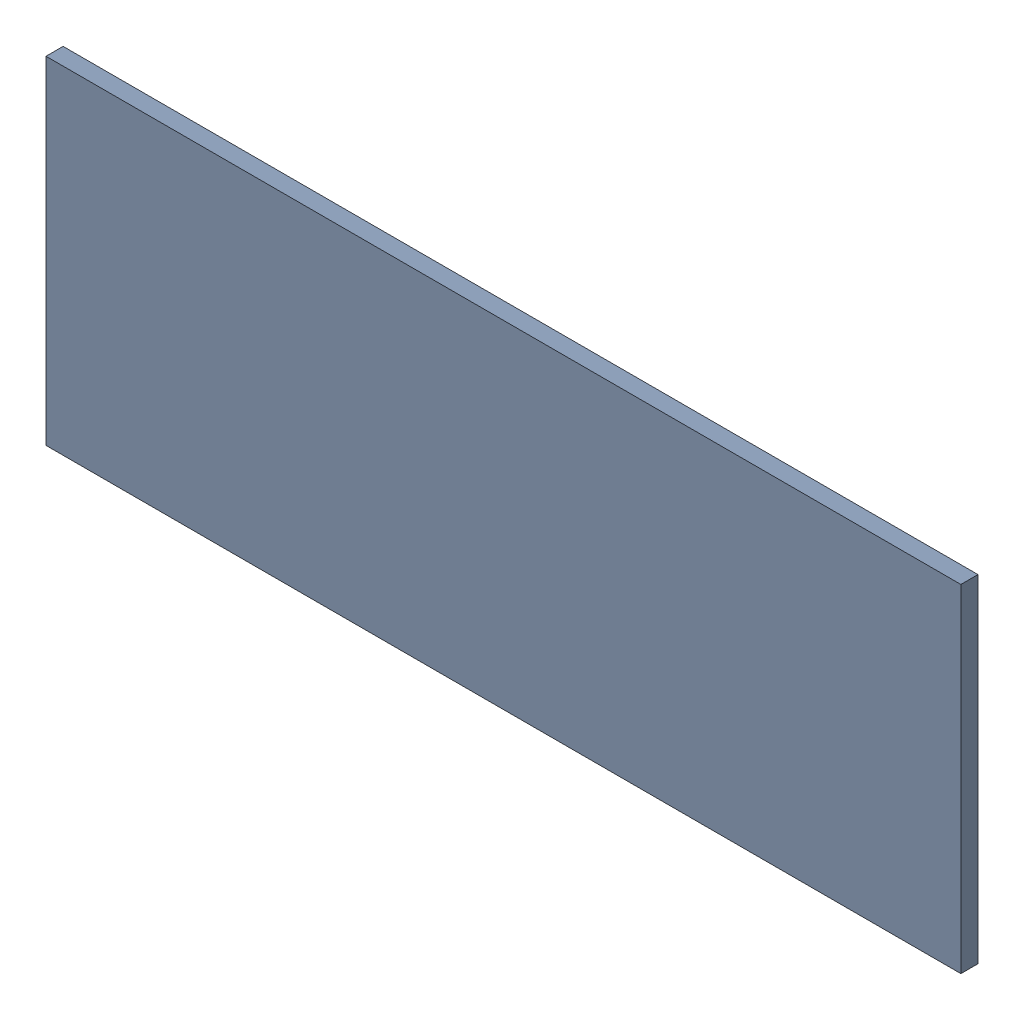
SolidWorks assembly Pad RAK4600-24(29.2mm,15mm) on Top Layer, configuration Predeterminado. Lengths in mm.
Overall size (1.9 0.7 0.04).
2 component instances, 1 part files, 0 mates.
Components (placement in the parent):
- Pad RAK4600-24(29.2mm,15mm) on Top Layer-1-1: Pad RAK4600-24(29.2mm,15mm) on Top Layer-1 [Predeterminado] at (-68.317 -44.187 -0.0457) size (1.9 0.7 0.04)
  - Pad RAK4600-24(29.2mm,15mm) on Top Layer-Part-1-1: Pad RAK4600-24(29.2mm,15mm) on Top Layer-Part-1 [Predeterminado] at origin size (1.9 0.7 0.04)
